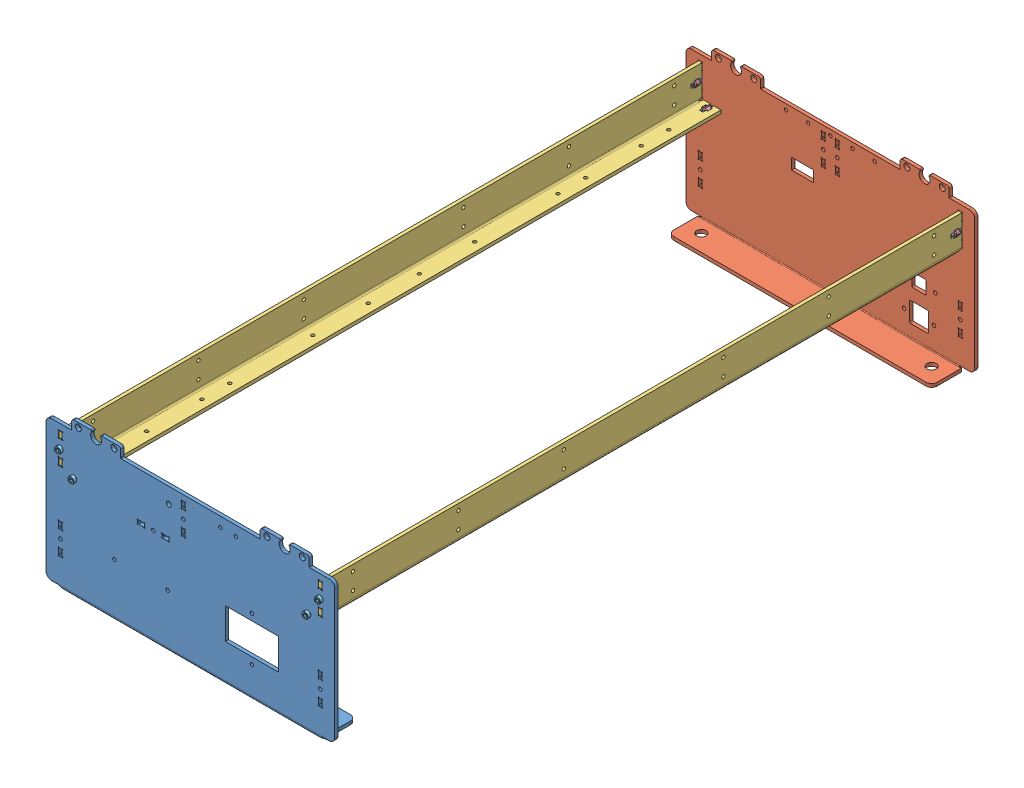
SolidWorks assembly ZorroChassis, configuration Default. Lengths in mm.
Overall size (260.35 138.87 586.29).
20 component instances, 5 part files, 51 mates.
Components (placement in the parent):
- ChassisBackPlate-1: ChassisBackPlate [Default] at (-181.486 448.7837 -85.9696) size (260.35 138.87 30.49)
- ChassisFrontPlate-1: ChassisFrontPlate [Default] at (356.5344 448.7837 -659.9695) x (-1 0 0) z (0 0 -1) size (260.35 138.87 30.49)
- ChassisSidePlate-1: ChassisSidePlate [Default] at (-163.7656 19.1363 -785.5189) x (-1 0 0) z (0 0 -1) size (20.15 31.34 580)
- ChassisSidePlate-2: ChassisSidePlate [Default] at (67.5844 19.1363 39.5799) size (20.15 31.34 580)
- 90576A102_ZINC-PLATED CLASS 8 STL NYLON-INSERT LOCKNUT-1: 90576A102_ZINC-PLATED CLASS 8 STL NYLON-INSERT LOCKNUT [90576A102] at (69.0844 727.9199 -657.1695) x (0 -1 0) z (-1 0 0) size (5.5 4.1 6.35)
- 91292A114_TYPE 18-8 SS SOCKET HEAD CAP SCREW-1: 91292A114_TYPE 18-8 SS SOCKET HEAD CAP SCREW [91292A114] at (69.0844 727.9199 -650.9695) x (-0.962816 0.270159 0) z (0 0 1) size (5.5 5.5 15.58)
- 91292A114_TYPE 18-8 SS SOCKET HEAD CAP SCREW-2: 91292A114_TYPE 18-8 SS SOCKET HEAD CAP SCREW [91292A114] at (-165.2656 727.9199 -650.9695) size (5.5 5.5 15.58)
- 90576A102_ZINC-PLATED CLASS 8 STL NYLON-INSERT LOCKNUT-2: 90576A102_ZINC-PLATED CLASS 8 STL NYLON-INSERT LOCKNUT [90576A102] at (-165.2656 727.9199 -657.1695) x (-0.866025 0.5 0) z (0.5 0.866025 0) size (5.5 4.1 6.35)
- 91292A114_TYPE 18-8 SS SOCKET HEAD CAP SCREW-3: 91292A114_TYPE 18-8 SS SOCKET HEAD CAP SCREW [91292A114] at (69.0844 727.9199 -94.9696) x (-1 0 0) z (0 0 -1) size (5.5 5.5 15.58)
- 91292A114_TYPE 18-8 SS SOCKET HEAD CAP SCREW-4: 91292A114_TYPE 18-8 SS SOCKET HEAD CAP SCREW [91292A114] at (-165.2656 727.9199 -94.9696) x (-1 0 0) z (0 0 -1) size (5.5 5.5 15.58)
- 90576A102_ZINC-PLATED CLASS 8 STL NYLON-INSERT LOCKNUT-3: 90576A102_ZINC-PLATED CLASS 8 STL NYLON-INSERT LOCKNUT [90576A102] at (69.0844 727.9199 -88.7696) x (0 -1 0) z (1 0 0) size (5.5 4.1 6.35)
- 90576A102_ZINC-PLATED CLASS 8 STL NYLON-INSERT LOCKNUT-4: 90576A102_ZINC-PLATED CLASS 8 STL NYLON-INSERT LOCKNUT [90576A102] at (-165.2656 727.9199 -88.7696) x (0.866025 -0.5 0) z (0.5 0.866025 0) size (5.5 4.1 6.35)
- 90576A102_ZINC-PLATED CLASS 8 STL NYLON-INSERT LOCKNUT-5: 90576A102_ZINC-PLATED CLASS 8 STL NYLON-INSERT LOCKNUT [90576A102] at (58.4344 710.6698 -657.1695) x (-0.5 -0.866025 0) z (-0.866025 0.5 0) size (5.5 4.1 6.35)
- 90576A102_ZINC-PLATED CLASS 8 STL NYLON-INSERT LOCKNUT-7: 90576A102_ZINC-PLATED CLASS 8 STL NYLON-INSERT LOCKNUT [90576A102] at (-154.6157 710.6698 -657.1695) x (0.5 -0.866025 0) z (-0.866025 -0.5 0) size (5.5 4.1 6.35)
- 90576A102_ZINC-PLATED CLASS 8 STL NYLON-INSERT LOCKNUT-9: 90576A102_ZINC-PLATED CLASS 8 STL NYLON-INSERT LOCKNUT [90576A102] at (58.0015 710.6698 -88.7696) x (-0.5 0.866025 0) z (-0.866025 -0.5 0) size (5.5 4.1 6.35)
- 90576A102_ZINC-PLATED CLASS 8 STL NYLON-INSERT LOCKNUT-10: 90576A102_ZINC-PLATED CLASS 8 STL NYLON-INSERT LOCKNUT [90576A102] at (-153.0485 710.6698 -88.7696) x (0.5 0.866025 0) z (-0.866025 0.5 0) size (5.5 4.1 6.35)
- 91292A114_TYPE 18-8 SS SOCKET HEAD CAP SCREW-5: 91292A114_TYPE 18-8 SS SOCKET HEAD CAP SCREW [91292A114] at (58.4344 710.6698 -650.9695) size (5.5 5.5 15.58)
- 91292A114_TYPE 18-8 SS SOCKET HEAD CAP SCREW-6: 91292A114_TYPE 18-8 SS SOCKET HEAD CAP SCREW [91292A114] at (-154.6157 710.6698 -650.9695) size (5.5 5.5 15.58)
- 91292A114_TYPE 18-8 SS SOCKET HEAD CAP SCREW-7: 91292A114_TYPE 18-8 SS SOCKET HEAD CAP SCREW [91292A114] at (58.0015 710.6698 -94.9696) x (1 0 0) z (0 0 -1) size (5.5 5.5 15.58)
- 91292A114_TYPE 18-8 SS SOCKET HEAD CAP SCREW-8: 91292A114_TYPE 18-8 SS SOCKET HEAD CAP SCREW [91292A114] at (-153.0485 710.6698 -94.9696) x (1 0 0) z (0 0 -1) size (5.5 5.5 15.58)
Mates (geometry in assembly coordinates):
- Width1: width anti-aligned: plane of ChassisSidePlate-2 through (70.5844 719.8199 -83.4695) normal (1 0 0); plane of ChassisSidePlate-2 through (67.5844 719.8199 -83.4695) normal (-1 0 0); plane of ChassisFrontPlate-1 through (70.7344 740.7539 -662.9695) normal (-1 0 0); plane of ChassisFrontPlate-1 through (67.4345 736.2859 -662.9695) normal (1 0 0)
- Width2: width anti-aligned: plane of ChassisSidePlate-2 through (67.5844 741.5199 -83.4695) normal (0 1 0); plane of ChassisSidePlate-2 through (67.5844 735.5199 -662.4695) normal (0 -1 0); plane of ChassisFrontPlate-1 through (68.3005 741.6199 -662.9695) normal (0 -1 0); plane of ChassisFrontPlate-1 through (69.8684 735.4199 -662.9695) normal (0 1 0)
- Coincident1: coincident anti-aligned: plane of ChassisFrontPlate-1 through (-173.2656 742.3113 -659.9695) normal (0 0 1); plane of ChassisSidePlate-2 through (67.5844 734.6539 -659.9695) normal (0 0 -1)
- Width3: width anti-aligned: plane of ChassisFrontPlate-1 through (-163.6156 740.7539 -662.9695) normal (-1 0 0); plane of ChassisFrontPlate-1 through (-166.9155 736.2859 -662.9695) normal (1 0 0); plane of ChassisSidePlate-1 through (-163.7656 719.8199 -662.4695) normal (1 0 0); plane of ChassisSidePlate-1 through (-166.7656 719.8199 -662.4695) normal (-1 0 0)
- Width4: width anti-aligned: plane of ChassisSidePlate-1 through (-163.7656 741.5199 -662.4695) normal (0 1 0); plane of ChassisSidePlate-1 through (-163.7656 735.5199 -662.4695) normal (0 -1 0); plane of ChassisFrontPlate-1 through (-166.0495 741.6199 -662.9695) normal (0 -1 0); plane of ChassisFrontPlate-1 through (-164.4816 735.4199 -662.9695) normal (0 1 0)
- Coincident3: coincident anti-aligned: plane of ChassisFrontPlate-1 through (-173.2656 742.3113 -659.9695) normal (0 0 1); plane of ChassisSidePlate-1 through (-163.7656 734.6539 -659.9695) normal (0 0 -1)
- Width5: width anti-aligned: plane of ChassisSidePlate-2 through (70.5844 719.8199 -83.4695) normal (1 0 0); plane of ChassisSidePlate-2 through (67.5844 719.8199 -83.4695) normal (-1 0 0); plane of ChassisBackPlate-1 through (70.7344 736.2859 -82.9696) normal (-1 0 0); plane of ChassisBackPlate-1 through (67.4345 740.7539 -82.9696) normal (1 0 0)
- Width6: width anti-aligned: plane of ChassisSidePlate-2 through (67.5844 741.5199 -83.4695) normal (0 1 0); plane of ChassisSidePlate-2 through (67.5844 735.5199 -83.4695) normal (0 -1 0); plane of ChassisBackPlate-1 through (69.8684 741.6199 -82.9696) normal (0 -1 0); plane of ChassisBackPlate-1 through (68.3005 735.4199 -82.9696) normal (0 1 0)
- Width7: width anti-aligned: plane of ChassisSidePlate-1 through (-163.7656 719.8199 -662.4695) normal (1 0 0); plane of ChassisSidePlate-1 through (-166.7656 719.8199 -662.4695) normal (-1 0 0); plane of ChassisBackPlate-1 through (-163.6156 736.2859 -82.9696) normal (-1 0 0); plane of ChassisBackPlate-1 through (-166.9155 740.7539 -82.9696) normal (1 0 0)
- Width8: width anti-aligned: plane of ChassisSidePlate-1 through (-163.7656 741.5199 -662.4695) normal (0 1 0); plane of ChassisSidePlate-1 through (-163.7656 735.5199 -83.4695) normal (0 -1 0); plane of ChassisBackPlate-1 through (-164.4816 741.6199 -82.9696) normal (0 -1 0); plane of ChassisBackPlate-1 through (-166.0495 735.4199 -82.9696) normal (0 1 0)
- Coincident4: coincident anti-aligned: plane of ChassisBackPlate-1 through (77.0844 742.3113 -85.9696) normal (0 0 -1); plane of ChassisSidePlate-1 through (-163.7656 734.6539 -85.9696) normal (0 0 1)
- Coincident5: coincident anti-aligned: plane of ChassisSidePlate-2 through (67.5844 724.9772 -657.1695) normal (0 0 1); plane of 90576A102_ZINC-PLATED CLASS 8 STL NYLON-INSERT LOCKNUT-1 through (70.6722 725.1699 -657.1695) normal (0 0 -1)
- Concentric10: concentric aligned: cylinder of ChassisFrontPlate-1 through (69.0844 727.9199 -662.9695) axis (0 0 1) radius 1.6; cone of 91292A114_TYPE 18-8 SS SOCKET HEAD CAP SCREW-1 through (69.0844 727.9199 -663.2445) axis (0 0 1)
- Coincident6: coincident anti-aligned: plane of ChassisFrontPlate-1 through (-173.2656 742.3113 -662.9695) normal (0 0 -1); plane of 91292A114_TYPE 18-8 SS SOCKET HEAD CAP SCREW-1 through (69.0844 727.9199 -662.9695) normal (0 0 1)
- Concentric13: concentric anti-aligned: circle of 90576A102_ZINC-PLATED CLASS 8 STL NYLON-INSERT LOCKNUT-1; circle of 91292A114_TYPE 18-8 SS SOCKET HEAD CAP SCREW-1
- Parallel1: parallel anti-aligned: plane of ChassisSidePlate-2 through (67.5844 730.8772 -657.1695) normal (0 -1 0); plane of 90576A102_ZINC-PLATED CLASS 8 STL NYLON-INSERT LOCKNUT-1 through (70.6722 730.6699 -653.1695) normal (0 1 0)
- Concentric14: concentric aligned: cylinder of ChassisFrontPlate-1 through (-165.2656 727.9199 -662.9695) axis (0 0 1) radius 1.6; circle of 91292A114_TYPE 18-8 SS SOCKET HEAD CAP SCREW-2
- Coincident7: coincident anti-aligned: plane of ChassisFrontPlate-1 through (-173.2656 742.3113 -662.9695) normal (0 0 -1); circle of 91292A114_TYPE 18-8 SS SOCKET HEAD CAP SCREW-2
- Parallel2: parallel aligned: plane of ChassisSidePlate-1 through (-163.7656 724.9772 -652.9695) normal (0 1 0); plane of 90576A102_ZINC-PLATED CLASS 8 STL NYLON-INSERT LOCKNUT-2 through (-163.6779 730.6699 -653.1695) normal (0 1 0)
- Concentric15: concentric anti-aligned: cylinder of 91292A114_TYPE 18-8 SS SOCKET HEAD CAP SCREW-2 through (-165.2656 727.9199 -665.9695) axis (0 0 1) radius 2.75; circle of 90576A102_ZINC-PLATED CLASS 8 STL NYLON-INSERT LOCKNUT-2
- Coincident8: coincident anti-aligned: plane of ChassisSidePlate-1 through (-163.7656 724.9772 -657.1695) normal (0 0 1); plane of 90576A102_ZINC-PLATED CLASS 8 STL NYLON-INSERT LOCKNUT-2 through (-168.441 727.9199 -657.1695) normal (0 0 -1)
- Concentric16: concentric anti-aligned: cylinder of ChassisBackPlate-1 through (-165.2656 727.9199 -82.9696) axis (0 0 -1) radius 1.6; circle of 90576A102_ZINC-PLATED CLASS 8 STL NYLON-INSERT LOCKNUT-4
- Concentric17: concentric anti-aligned: cylinder of ChassisBackPlate-1 through (69.0844 727.9199 -82.9696) axis (0 0 -1) radius 1.6; circle of 90576A102_ZINC-PLATED CLASS 8 STL NYLON-INSERT LOCKNUT-3
- Coincident9: coincident anti-aligned: plane of ChassisSidePlate-2 through (67.5844 724.9772 -88.7696) normal (0 0 -1); plane of 90576A102_ZINC-PLATED CLASS 8 STL NYLON-INSERT LOCKNUT-3 through (67.4967 725.1699 -88.7696) normal (0 0 1)
- Parallel3: parallel anti-aligned: plane of ChassisSidePlate-2 through (67.5844 730.8772 -88.7696) normal (0 -1 0); plane of 90576A102_ZINC-PLATED CLASS 8 STL NYLON-INSERT LOCKNUT-3 through (67.4967 730.6699 -92.7696) normal (0 1 0)
- Coincident10: coincident anti-aligned: plane of ChassisBackPlate-1 through (77.0844 742.3113 -82.9696) normal (0 0 1); plane of 91292A114_TYPE 18-8 SS SOCKET HEAD CAP SCREW-3 through (69.0844 727.9199 -82.9696) normal (0 0 -1)
- Concentric18: concentric anti-aligned: circle of ChassisBackPlate-1; cylinder of 91292A114_TYPE 18-8 SS SOCKET HEAD CAP SCREW-3 through (69.0844 727.9199 -79.9696) axis (0 0 -1) radius 2.75
- Coincident11: coincident anti-aligned: plane of ChassisSidePlate-1 through (-163.7656 729.5199 -88.7696) normal (0 0 -1); plane of 90576A102_ZINC-PLATED CLASS 8 STL NYLON-INSERT LOCKNUT-4 through (-163.6779 725.1699 -88.7696) normal (0 0 1)
- Parallel4: parallel anti-aligned: plane of ChassisSidePlate-1 through (-163.7656 730.8772 -88.7696) normal (0 -1 0); plane of 90576A102_ZINC-PLATED CLASS 8 STL NYLON-INSERT LOCKNUT-4 through (-166.8533 730.6699 -92.7696) normal (0 1 0)
- Coincident12: coincident anti-aligned: plane of ChassisBackPlate-1 through (77.0844 742.3113 -82.9696) normal (0 0 1); circle of 91292A114_TYPE 18-8 SS SOCKET HEAD CAP SCREW-4
- Concentric19: concentric aligned: cylinder of ChassisBackPlate-1 through (-165.2656 727.9199 -82.9696) axis (0 0 -1) radius 1.6; cylinder of 91292A114_TYPE 18-8 SS SOCKET HEAD CAP SCREW-4 through (-165.2656 727.9199 -79.9696) axis (0 0 -1) radius 2.75
- Coincident13: coincident anti-aligned: plane of ChassisSidePlate-2 through (60.0406 713.1761 -88.7696) normal (0 0 -1); plane of 90576A102_ZINC-PLATED CLASS 8 STL NYLON-INSERT LOCKNUT-9 through (58.0015 713.8452 -88.7696) normal (0 0 1)
- Slot1: slot aligned: cylinder of ChassisBackPlate-1 through (58.4345 710.6693 -82.9696) axis (0 0 -1) radius 1.6501; cylinder of 91292A114_TYPE 18-8 SS SOCKET HEAD CAP SCREW-7 through (58.0015 710.6698 -79.9696) axis (0 0 -1) radius 2.75; cylinder of ChassisBackPlate-1 through (56.4345 710.6693 -82.9696) axis (0 0 -1) radius 1.6501
- Coincident14: coincident anti-aligned: plane of ChassisBackPlate-1 through (77.0844 742.3113 -82.9696) normal (0 0 1); plane of 91292A114_TYPE 18-8 SS SOCKET HEAD CAP SCREW-7 through (58.0015 710.6698 -82.9696) normal (0 0 -1)
- Concentric22: concentric anti-aligned: circle of 90576A102_ZINC-PLATED CLASS 8 STL NYLON-INSERT LOCKNUT-9; cylinder of 91292A114_TYPE 18-8 SS SOCKET HEAD CAP SCREW-7 through (58.0015 710.6698 -79.9696) axis (0 0 -1) radius 2.75
- Parallel7: parallel anti-aligned: plane of ChassisSidePlate-2 through (61.3979 713.1761 -88.7696) normal (-1 0 0); plane of 90576A102_ZINC-PLATED CLASS 8 STL NYLON-INSERT LOCKNUT-9 through (60.7515 712.2575 -92.7696) normal (1 0 0)
- Coincident15: coincident anti-aligned: plane of ChassisSidePlate-1 through (-151.6791 713.1761 -88.7696) normal (0 0 -1); plane of 90576A102_ZINC-PLATED CLASS 8 STL NYLON-INSERT LOCKNUT-10 through (-150.2985 712.2575 -88.7696) normal (0 0 1)
- Slot2: slot aligned: cylinder of 91292A114_TYPE 18-8 SS SOCKET HEAD CAP SCREW-8 through (-153.0485 710.6698 -79.9696) axis (0 0 -1) radius 2.75; cylinder of ChassisBackPlate-1 through (-154.6155 710.6698 -82.9696) axis (0 0 -1) radius 1.6501; cylinder of ChassisBackPlate-1 through (-152.6155 710.6698 -82.9696) axis (0 0 -1) radius 1.6501
- Coincident16: coincident anti-aligned: plane of ChassisBackPlate-1 through (77.0844 742.3113 -82.9696) normal (0 0 1); plane of 91292A114_TYPE 18-8 SS SOCKET HEAD CAP SCREW-8 through (-153.0485 710.6698 -82.9696) normal (0 0 -1)
- Concentric23: concentric anti-aligned: circle of 90576A102_ZINC-PLATED CLASS 8 STL NYLON-INSERT LOCKNUT-10; cylinder of 91292A114_TYPE 18-8 SS SOCKET HEAD CAP SCREW-8 through (-153.0485 710.6698 -79.9696) axis (0 0 -1) radius 2.75
- Parallel8: parallel anti-aligned: plane of ChassisSidePlate-1 through (-157.5791 713.1761 -88.7696) normal (1 0 0); plane of 90576A102_ZINC-PLATED CLASS 8 STL NYLON-INSERT LOCKNUT-10 through (-155.7985 709.0821 -92.7696) normal (-1 0 0)
- Coincident17: coincident anti-aligned: plane of ChassisSidePlate-1 through (-156.2218 713.1761 -657.1695) normal (0 0 1); plane of 90576A102_ZINC-PLATED CLASS 8 STL NYLON-INSERT LOCKNUT-7 through (-151.8657 709.0821 -657.1695) normal (0 0 -1)
- Concentric24: concentric anti-aligned: circle of 90576A102_ZINC-PLATED CLASS 8 STL NYLON-INSERT LOCKNUT-7; cylinder of 91292A114_TYPE 18-8 SS SOCKET HEAD CAP SCREW-6 through (-154.6157 710.6698 -665.9695) axis (0 0 1) radius 2.75
- Slot3: slot aligned: cylinder of ChassisFrontPlate-1 through (-154.6157 710.6693 -662.9695) axis (0 0 1) radius 1.6501; cylinder of 91292A114_TYPE 18-8 SS SOCKET HEAD CAP SCREW-6 through (-154.6157 710.6698 -665.9695) axis (0 0 1) radius 2.75; cylinder of ChassisFrontPlate-1 through (-152.6157 710.6693 -662.9695) axis (0 0 1) radius 1.6501
- Coincident20: coincident anti-aligned: plane of ChassisFrontPlate-1 through (-173.2656 742.3113 -662.9695) normal (0 0 -1); plane of 91292A114_TYPE 18-8 SS SOCKET HEAD CAP SCREW-6 through (-154.6157 710.6698 -662.9695) normal (0 0 1)
- Parallel9: parallel aligned: plane of ChassisSidePlate-1 through (-157.5791 713.1761 -657.1695) normal (1 0 0); plane of 90576A102_ZINC-PLATED CLASS 8 STL NYLON-INSERT LOCKNUT-7 through (-151.8657 709.0821 -653.1695) normal (1 0 0)
- Concentric25: concentric anti-aligned: cone of 90576A102_ZINC-PLATED CLASS 8 STL NYLON-INSERT LOCKNUT-5 through (58.4344 710.6698 -656.9711) axis (0 0 -1); cylinder of 91292A114_TYPE 18-8 SS SOCKET HEAD CAP SCREW-5 through (58.4344 710.6698 -665.9695) axis (0 0 1) radius 2.75
- Coincident21: coincident anti-aligned: plane of ChassisSidePlate-2 through (55.4979 713.1761 -657.1695) normal (0 0 1); plane of 90576A102_ZINC-PLATED CLASS 8 STL NYLON-INSERT LOCKNUT-5 through (58.4344 707.4944 -657.1695) normal (0 0 -1)
- Slot5: slot aligned: cylinder of ChassisFrontPlate-1 through (56.4344 710.6698 -662.9695) axis (0 0 1) radius 1.6501; cylinder of 91292A114_TYPE 18-8 SS SOCKET HEAD CAP SCREW-5 through (58.4344 710.6698 -665.9695) axis (0 0 1) radius 2.75; cylinder of ChassisFrontPlate-1 through (58.4344 710.6698 -662.9695) axis (0 0 1) radius 1.6501
- Coincident22: coincident anti-aligned: plane of ChassisFrontPlate-1 through (-173.2656 742.3113 -662.9695) normal (0 0 -1); plane of 91292A114_TYPE 18-8 SS SOCKET HEAD CAP SCREW-5 through (58.4344 710.6698 -662.9695) normal (0 0 1)
- Parallel11: parallel anti-aligned: plane of ChassisSidePlate-2 through (61.3979 713.1761 -657.1695) normal (-1 0 0); plane of 90576A102_ZINC-PLATED CLASS 8 STL NYLON-INSERT LOCKNUT-5 through (61.1844 709.0821 -653.1695) normal (1 0 0)
